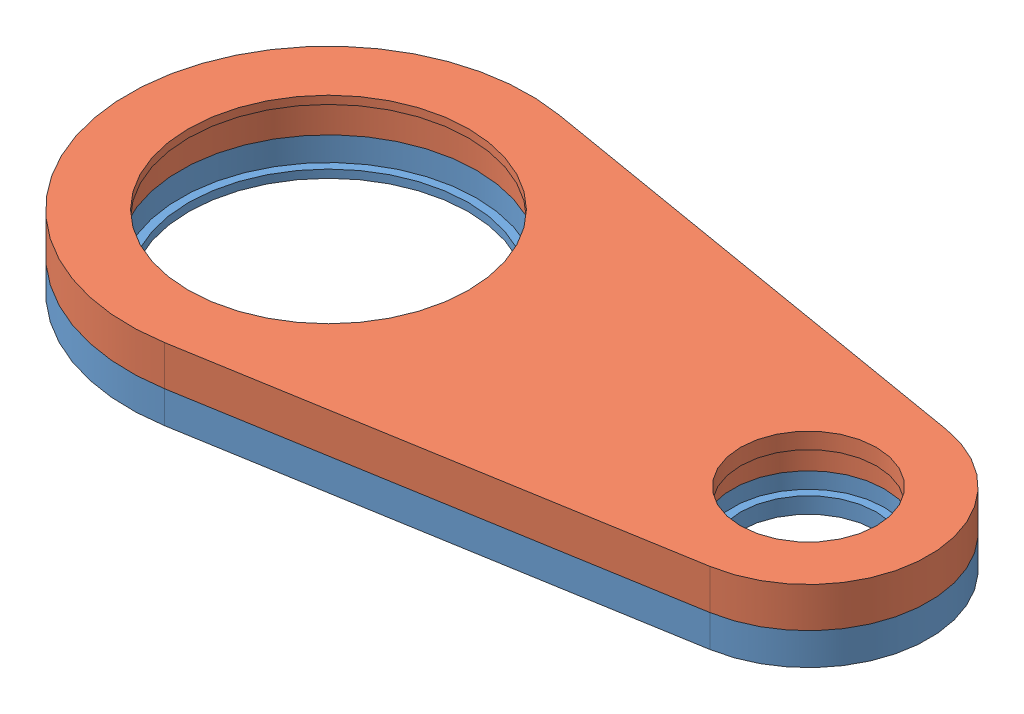
SolidWorks assembly hip_link2_bearing_cap_assem, configuration 기본. Lengths in mm.
Overall size (100 9 50).
2 component instances, 2 part files, 3 mates.
Components (placement in the parent):
- Hip Link 2 Bearing Cap_part1-1: Hip Link 2 Bearing Cap_part1 [기본] at origin size (100 4 50)
- Hip Link 2 Bearing Cap_part2-1: Hip Link 2 Bearing Cap_part2 [기본] at (0 -1 0) size (100 5 50)
Mates (geometry in assembly coordinates):
- 동심1: concentric aligned: cylinder of Hip Link 2 Bearing Cap_part1-1 through (60 7 0) axis (0 -1 0) radius 9.5; cylinder of Hip Link 2 Bearing Cap_part2-1 through (60 7 0) axis (0 -1 0) radius 9.5
- 동심2: concentric aligned: cylinder of Hip Link 2 Bearing Cap_part1-1 through (0 9 0) axis (0 -1 0) radius 18.5; cylinder of Hip Link 2 Bearing Cap_part2-1 through (0 9 0) axis (0 -1 0) radius 18.5
- 일치1: coincident anti-aligned: plane of Hip Link 2 Bearing Cap_part1-1 through (-1111 4 33.8225) normal (0 1 0); plane of Hip Link 2 Bearing Cap_part2-1 through (-1111 4 33.8225) normal (0 -1 0)
